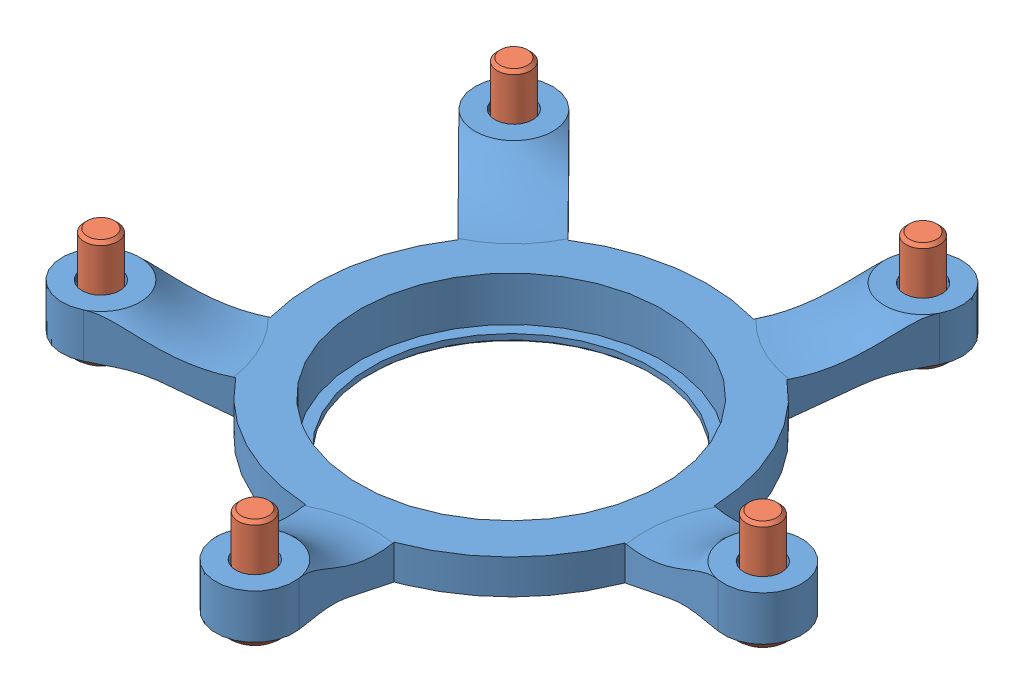
SolidWorks assembly Cloche, configuration Défaut. Lengths in mm.
Overall size (78.76 11.7 77.66).
6 component instances, 2 part files, 10 mates.
Components (placement in the parent):
- Cloche-1: Cloche [Défaut] at (-6.7592 -2.1561 0) x (-0.888048 0 -0.459752) z (-0.459752 0 0.888048) size (59.31 8.37 56.75)
- socket button head screw_iso-1: socket button head screw_iso [ISO 7380 - M3 x 8 - 8N] at (5.884 -4.8061 -24.4213) x (0 1 0) z (0 0 1) size (9.65 5.7 5.7)
- socket button head screw_iso-2: socket button head screw_iso [ISO 7380 - M3 x 8 - 8N] at (-26.0783 -4.8061 -19.571) x (0 1 0) z (0 0 1) size (9.65 5.7 5.7)
- socket button head screw_iso-7: socket button head screw_iso [ISO 7380 - M3 x 8 - 8N] at (-2.6332 -4.8061 27.1887) x (0 1 0) z (0 0 1) size (9.65 5.7 5.7)
- socket button head screw_iso-8: socket button head screw_iso [ISO 7380 - M3 x 8 - 8N] at (20.3738 -4.8061 4.4778) x (0 1 0) z (0 0 1) size (9.65 5.7 5.7)
- socket button head screw_iso-9: socket button head screw_iso [ISO 7380 - M3 x 8 - 8N] at (-31.3422 -4.8061 12.3258) x (0 1 0) z (0 0 1) size (9.65 5.7 5.7)
Mates (geometry in assembly coordinates):
- Coaxiale2209: concentric anti-aligned: cylinder of Cloche-1 through (5.884 -6.1561 -24.4213) axis (0 1 0) radius 1.7; cylinder of socket button head screw_iso-1 through (5.884 -4.8061 -24.4213) axis (0 -1 0) radius 2.85
- Coïncidente267: coincident anti-aligned: plane of Cloche-1 through (-17.7932 -3.1561 21.3131) normal (0 -1 0); plane of socket button head screw_iso-1 through (4.384 -3.1561 -24.4213) normal (0 1 0)
- Coaxiale2210: concentric anti-aligned: cylinder of Cloche-1 through (-26.0783 -6.1561 -19.571) axis (0 1 0) radius 1.7; cylinder of socket button head screw_iso-2 through (-26.0783 -4.8061 -19.571) axis (0 -1 0) radius 2.85
- Coïncidente268: coincident anti-aligned: plane of Cloche-1 through (-17.7932 -3.1561 21.3131) normal (0 -1 0); plane of socket button head screw_iso-2 through (-27.5783 -3.1561 -19.571) normal (0 1 0)
- Coaxiale2211: concentric anti-aligned: cylinder of Cloche-1 through (-2.6332 -6.1561 27.1887) axis (0 1 0) radius 1.7; cylinder of socket button head screw_iso-7 through (-2.6332 -4.8061 27.1887) axis (0 -1 0) radius 2.85
- Coïncidente269: coincident anti-aligned: plane of Cloche-1 through (-17.7932 -3.1561 21.3131) normal (0 -1 0); plane of socket button head screw_iso-7 through (-4.1332 -3.1561 27.1887) normal (0 1 0)
- Coaxiale2212: concentric anti-aligned: cylinder of Cloche-1 through (20.3738 -6.1561 4.4778) axis (0 1 0) radius 1.7; cylinder of socket button head screw_iso-8 through (20.3738 -4.8061 4.4778) axis (0 -1 0) radius 2.85
- Coïncidente270: coincident anti-aligned: plane of Cloche-1 through (-17.7932 -3.1561 21.3131) normal (0 -1 0); plane of socket button head screw_iso-8 through (18.8738 -3.1561 4.4778) normal (0 1 0)
- Coaxiale22131: concentric anti-aligned: cylinder of Cloche-1 through (-31.3422 -6.1561 12.3258) axis (0 1 0) radius 1.7; cylinder of socket button head screw_iso-9 through (-31.3422 -4.8061 12.3258) axis (0 -1 0) radius 2.85
- Coïncidente2711: coincident anti-aligned: plane of Cloche-1 through (-17.7932 -3.1561 21.3131) normal (0 -1 0); plane of socket button head screw_iso-9 through (-32.8422 -3.1561 12.3258) normal (0 1 0)
